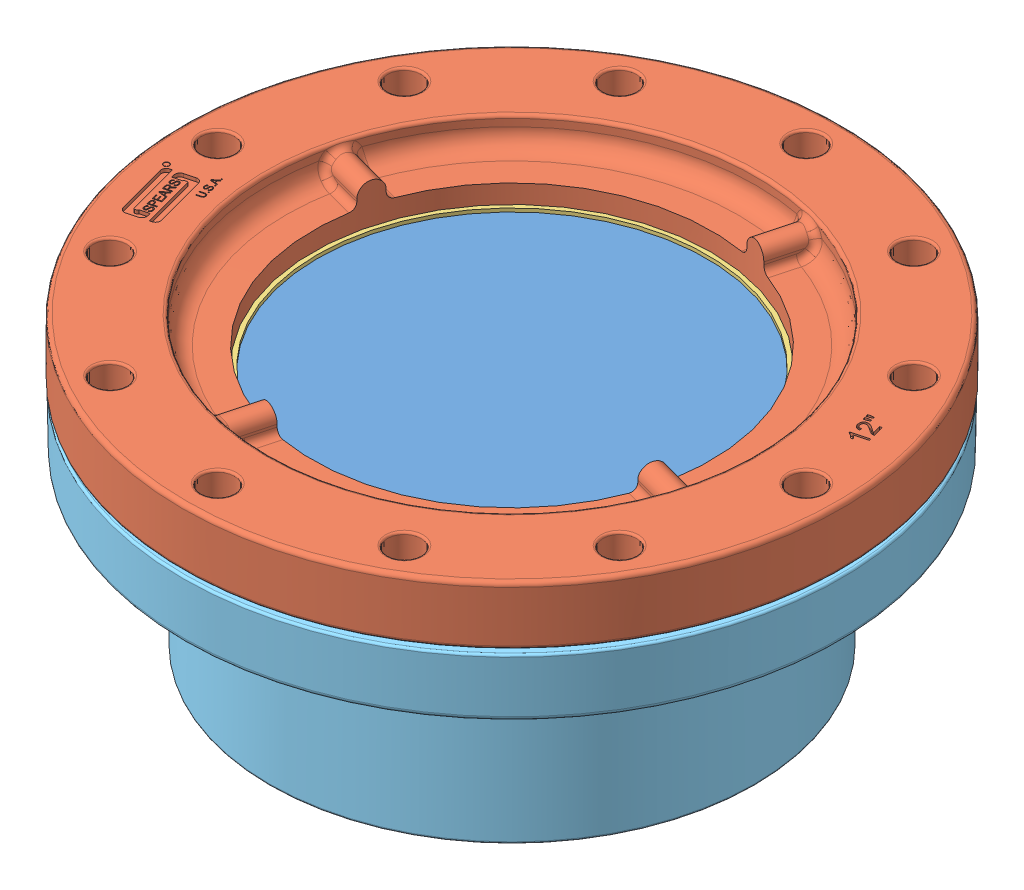
SolidWorks assembly FlangeAssembly, configuration TOP. Lengths in mm.
Overall size (483.62 211.77 483.62).
5 component instances, 5 part files, 8 mates.
Components (placement in the parent):
- GlassWindow-1: GlassWindow [Default] at (-12.7755 0.3445 2.1933) size (330.2 12.7 330.2)
- SPEARS 3D SC80-853-120-bored-1: SPEARS 3D SC80-853-120-bored [Default] at (-12.7755 6.6945 2.1933) x (0 1 0) z (0 0 1) size (45.16 483.62 483.62)
- BlindFlangeGasket-1: BlindFlangeGasket [Default] at (-12.7755 15.5845 2.1933) x (1 0 0) z (0 -1 0) size (330.2 330.2 2.54)
- SlipFlangeGasket-1: SlipFlangeGasket [Default] at (-12.7755 -2.1955 2.1933) x (1 0 0) z (0 1 0) size (330.2 330.2 2.54)
- SPEARS 3D SC80-851-120-1: SPEARS 3D SC80-851-120 [Default] at (-12.7755 4.1545 2.1933) x (0 -1 0) z (0 0 1) size (167.96 482.54 482.54)
Mates (geometry in assembly coordinates):
- Coincident1: coincident anti-aligned: plane of GlassWindow-1 through (-12.7755 13.0445 2.1933) normal (0 1 0); plane of BlindFlangeGasket-1 through (-12.7755 13.0445 2.1933) normal (0 -1 0)
- Concentric1: concentric anti-aligned: cylinder of GlassWindow-1 through (-12.7755 13.0445 2.1933) axis (0 -1 0) radius 165.1; cylinder of BlindFlangeGasket-1 through (-12.7755 13.0445 2.1933) axis (0 1 0) radius 165.1
- Coincident2: coincident aligned: circle of SPEARS 3D SC80-853-120-bored-1; plane of BlindFlangeGasket-1 through (-12.7755 15.5845 2.1933) normal (0 1 0)
- Concentric2: concentric anti-aligned: cylinder of GlassWindow-1 through (-12.7755 13.0445 2.1933) axis (0 -1 0) radius 165.1; cylinder of SPEARS 3D SC80-853-120-bored-1 through (-12.7755 4.4085 2.1933) axis (0 1 0) radius 146.05
- Coincident3: coincident anti-aligned: plane of GlassWindow-1 through (-12.7755 0.3445 2.1933) normal (0 -1 0); plane of SlipFlangeGasket-1 through (-12.7755 0.3445 2.1933) normal (0 1 0)
- Concentric3: concentric anti-aligned: circle of GlassWindow-1; cylinder of SlipFlangeGasket-1 through (-12.7755 0.3445 2.1933) axis (0 -1 0) radius 165.1
- Coincident4: coincident anti-aligned: plane of SlipFlangeGasket-1 through (-12.7755 -2.1955 2.1933) normal (0 -1 0); plane of SPEARS 3D SC80-851-120-1 through (-12.7755 -2.1955 2.1933) normal (0 1 0)
- Concentric4: concentric anti-aligned: circle of SlipFlangeGasket-1; circle of SPEARS 3D SC80-851-120-1
